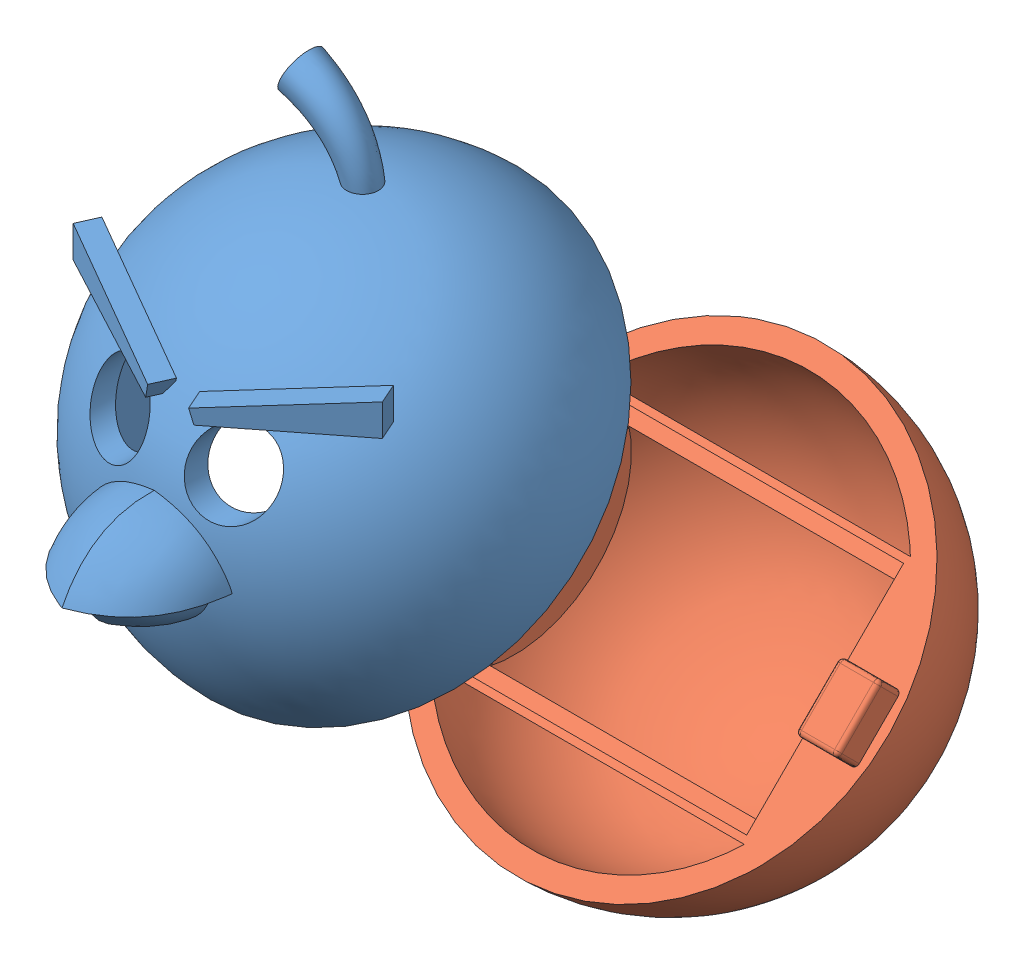
SolidWorks assembly Assemblage1, configuration Défaut. Lengths in mm.
Overall size (100 211.47 210.6).
2 component instances, 2 part files, 2 mates.
Components (placement in the parent):
- Angry bird-1: Angry bird [Défaut] at (-14.8963 -5.6514 109.7703) size (100 105.76 119.54)
- demi angry bird male-1: demi angry bird male [Défaut] at (-14.8963 -76.0028 39.4189) x (-1 0 0) z (0 -0.707107 -0.707107) size (100 100 56.6)
Mates (geometry in assembly coordinates):
- Parallèle1: parallel aligned: line of Angry bird-1 through (-62.8963 -0.3481 104.467) axis (1 0 0); line of demi angry bird male-1 through (-61.6963 -70.8409 34.257) axis (1 0 0)
- Coaxiale1: concentric aligned: circle of Angry bird-1; circle of demi angry bird male-1
